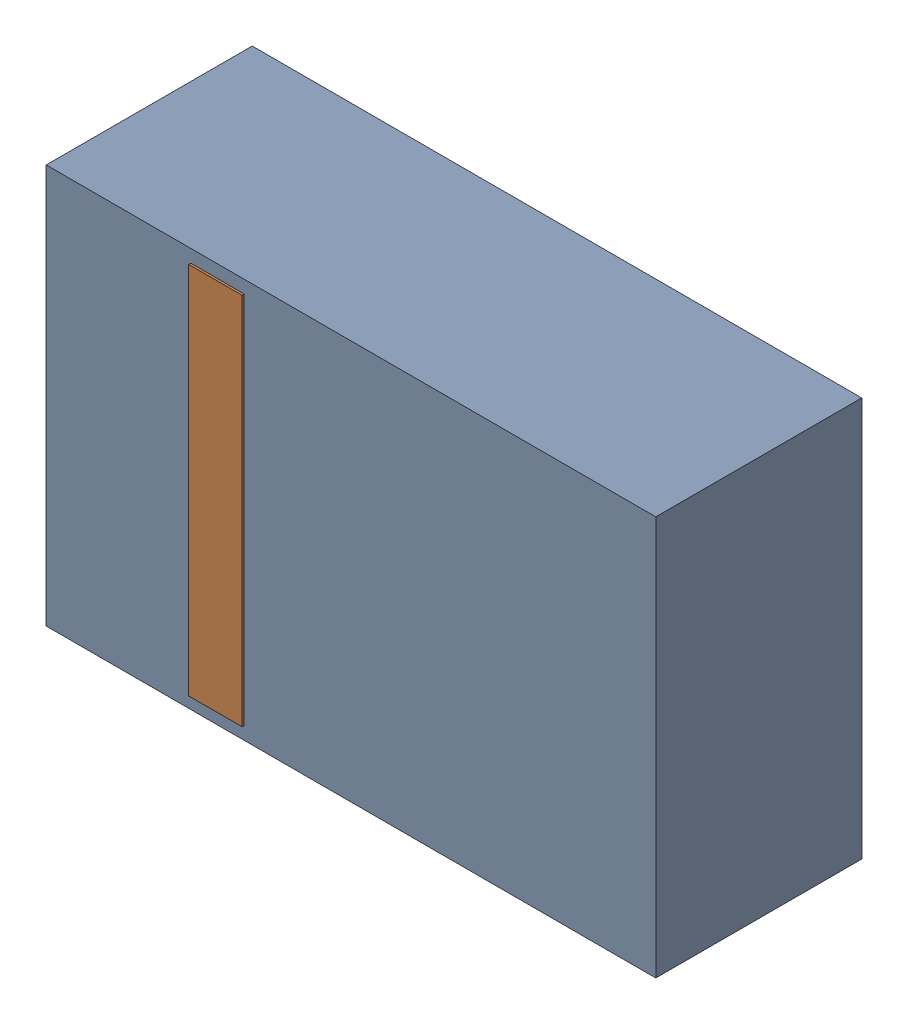
SolidWorks assembly D33, configuration Default. Lengths in mm.
Overall size (2.9 1.9 0.99).
4 component instances, 2 part files, 0 mates.
Components (placement in the parent):
- 905269392-1: 905269392 [Default] at (198.374 71.882 0) size (2.9 1.9 0.98)
  - Extruded_5-1: Extruded_5 [Default] at origin size (2.9 1.9 0.98)
- 905269800-1: 905269800 [Default] at (197.739 71.882 0.95) size (0.25 1.78 0.04)
  - Extruded_6-1: Extruded_6 [Default] at origin size (0.25 1.78 0.04)
